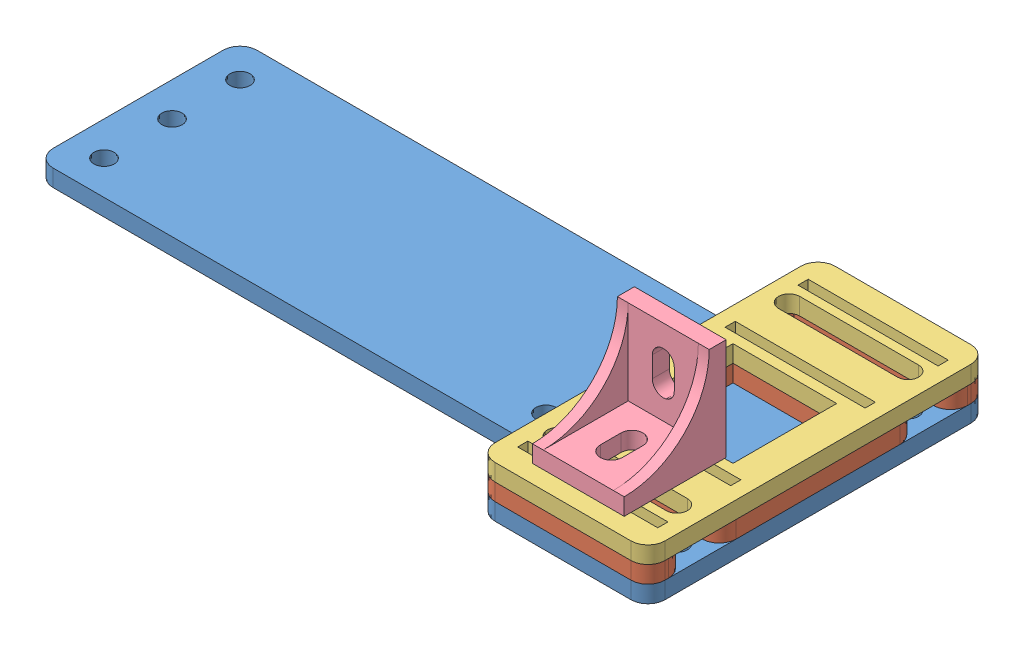
SolidWorks assembly Assem1, configuration Default. Lengths in mm.
Overall size (200 45 100).
4 component instances, 4 part files, 9 mates.
Components (placement in the parent):
- 腳底板固定片[01_v1.0]-1: 腳底板固定片[01_v1.0] [Default] at (-104.0287 100.2984 248.8742) size (200 5 100)
- 腳底板螺帽固定片[01_v1.0]-1: 腳底板螺帽固定片[01_v1.0] [Default] at (-29.0287 105.2984 248.8742) size (50 5 100)
- 腳底板螺帽固定片[02_v1.0]-1: 腳底板螺帽固定片[02_v1.0] [Default] at (-29.0287 110.2984 248.8742) size (50 5 100)
- 3030鋁擠型三角件M6[01-v1.0]-1: 3030鋁擠型三角件M6[01-v1.0] [Default] at (-29.7787 115.2984 278.6242) size (27 31.65 31.65)
Mates (geometry in assembly coordinates):
- Coincident1: coincident anti-aligned: plane of 腳底板固定片[01_v1.0]-1 through (-104.0287 105.2984 248.8742) normal (0 1 0); plane of 腳底板螺帽固定片[01_v1.0]-1 through (-29.0287 105.2984 248.8742) normal (0 -1 0)
- Coincident2: coincident aligned: plane of 腳底板固定片[01_v1.0]-1 through (-4.0287 105.2984 278.8742) normal (1 0 0); plane of 腳底板螺帽固定片[01_v1.0]-1 through (-4.0287 110.2984 298.8742) normal (1 0 0)
- Coincident3: coincident aligned: plane of 腳底板固定片[01_v1.0]-1 through (-54.0287 217.1018 298.8742) normal (0 0 1); plane of 腳底板螺帽固定片[01_v1.0]-1 through (-54.0287 110.2984 298.8742) normal (0 0 1)
- Coincident4: coincident anti-aligned: plane of 腳底板螺帽固定片[01_v1.0]-1 through (-29.0287 110.2984 248.8742) normal (0 1 0); plane of 腳底板螺帽固定片[02_v1.0]-1 through (-29.0287 110.2984 248.8742) normal (0 -1 0)
- Coincident5: coincident aligned: plane of 腳底板螺帽固定片[01_v1.0]-1 through (-54.0287 110.2984 298.8742) normal (0 0 1); plane of 腳底板螺帽固定片[02_v1.0]-1 through (-54.0287 115.2984 298.8742) normal (0 0 1)
- Coincident6: coincident aligned: plane of 腳底板螺帽固定片[01_v1.0]-1 through (-4.0287 110.2984 298.8742) normal (1 0 0); plane of 腳底板螺帽固定片[02_v1.0]-1 through (-4.0287 115.2984 198.8742) normal (1 0 0)
- Coincident7: coincident: plane of 腳底板螺帽固定片[02_v1.0]-1 through (-29.0287 115.2984 248.8742) normal (0 1 0); plane of 3030鋁擠型三角件M6[01-v1.0]-1 through (-32.5287 115.2984 278.6242) normal (0 -1 0)
- Distance1: distance = 0.5 mm: plane of 3030鋁擠型三角件M6[01-v1.0]-1 through (-43.2787 145.2984 263.6242) normal (0 0 -1); plane of 腳底板螺帽固定片[02_v1.0]-1 through (-44.2787 110.2984 264.1242) normal (0 0 -1)
- Distance3: distance = 2.5 mm anti-aligned: plane of 3030鋁擠型三角件M6[01-v1.0]-1 through (-16.2787 145.2984 293.6242) normal (1 0 0); plane of 腳底板螺帽固定片[02_v1.0]-1 through (-13.7787 110.2984 264.1242) normal (-1 0 0)
